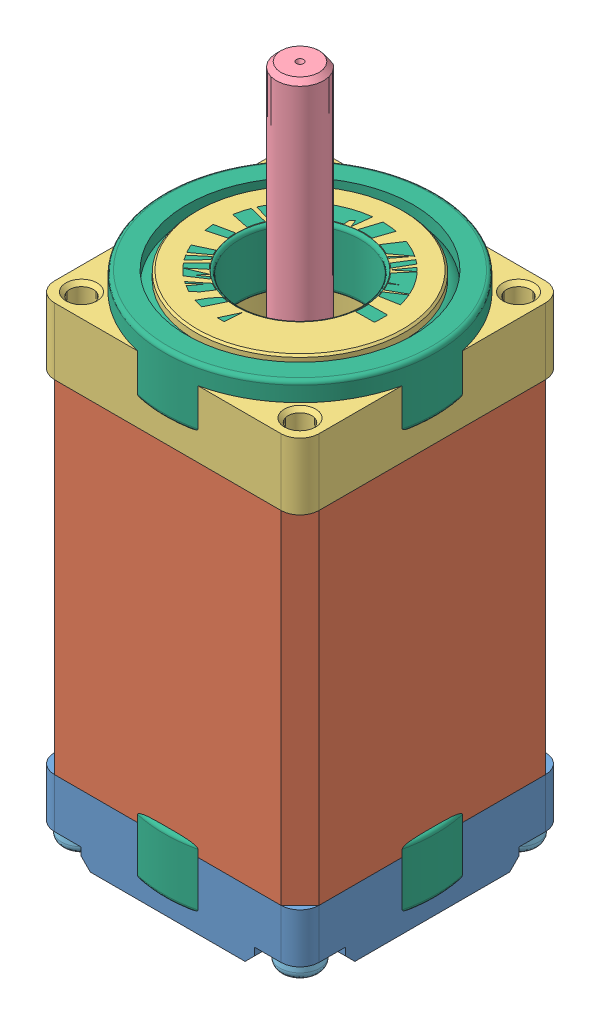
SolidWorks assembly Nema_11_motor_51mm, configuration По умолчанию. Lengths in mm.
Overall size (28.57 71.01 28.57).
10 component instances, 6 part files, 18 mates.
Components (placement in the parent):
- bottom_nema11-1: bottom_nema11 [По умолчанию] at origin size (27.85 7 27.85)
- middle_51_nema11-1: middle_51_nema11 [По умолчанию] at (0 7 0) size (27.85 36 27.85)
- top_nema11-1: top_nema11 [По умолчанию] at (0 43 0) size (27.85 9 27.85)
- shaft_51_nema11-1: shaft_51_nema11 [По умолчанию] at origin size (5 71 5)
- screw_51_nema11-1: screw_51_nema11 [По умолчанию] at (-11.5 1.8 -11.5) size (4.2 45.81 4.2)
- screw_51_nema11-8: screw_51_nema11 [По умолчанию] at (-11.5 1.8 11.5) size (4.2 45.81 4.2)
- screw_51_nema11-9: screw_51_nema11 [По умолчанию] at (11.5 1.8 -11.5) size (4.2 45.81 4.2)
- screw_51_nema11-10: screw_51_nema11 [По умолчанию] at (11.5 1.8 11.5) size (4.2 45.81 4.2)
- instrument ball bearing_68_iso-1: instrument ball bearing_68_iso [ISO 1224 - 190513 - R,Full,SI,NC,Full_68] at (0 48.825 0) x (0 1 0) z (0 0 1) size (6.35 28.57 28.57)
- instrument ball bearing_68_iso-2: instrument ball bearing_68_iso [ISO 1224 - 190513 - R,Full,SI,NC,Full_68] at (0 4.975 0) x (0 -1 0) z (0 0 1) size (6.35 28.57 28.57)
Mates (geometry in assembly coordinates):
- Совпадение1: coincident anti-aligned: plane of bottom_nema11-1 through (0 7 0) normal (0 1 0); plane of middle_51_nema11-1 through (0 7 0) normal (0 -1 0)
- Совпадение2: coincident aligned: plane of bottom_nema11-1 through (13.925 7 0) normal (1 0 0); plane of middle_51_nema11-1 through (13.925 43 13.925) normal (1 0 0)
- Совпадение3: coincident aligned: plane of bottom_nema11-1 through (0 7 13.925) normal (0 0 1); plane of middle_51_nema11-1 through (-13.925 43 13.925) normal (0 0 1)
- Концентричный1: concentric aligned: cylinder of bottom_nema11-1 through (11.5 7 11.5) axis (0 -1 0) radius 1.25; cylinder of top_nema11-1 through (11.5 50 11.5) axis (0 -1 0) radius 1.25
- Концентричный2: concentric aligned: cylinder of bottom_nema11-1 through (-11.5 7 -11.5) axis (0 -1 0) radius 1.25; cylinder of top_nema11-1 through (-11.5 50 -11.5) axis (0 -1 0) radius 1.25
- Совпадение5: coincident aligned: plane of bottom_nema11-1 through (0 0 0) normal (0 -1 0); plane of shaft_51_nema11-1 through (0 0 0) normal (0 -1 0)
- Концентричный4: concentric aligned: cylinder of bottom_nema11-1 through (-11.5 7 -11.5) axis (0 -1 0) radius 1.25; cylinder of screw_51_nema11-1 through (-11.5 45.8 -11.5) axis (0 -1 0) radius 1.25
- Совпадение6: coincident anti-aligned: plane of bottom_nema11-1 through (0 1.8 0) normal (0 -1 0); plane of screw_51_nema11-1 through (-11.5 1.8 -11.5) normal (0 1 0)
- Концентричный6: concentric aligned: cylinder of bottom_nema11-1 through (-11.5 7 11.5) axis (0 -1 0) radius 1.25; cylinder of screw_51_nema11-8 through (-11.5 45.8 11.5) axis (0 -1 0) radius 1.25
- Совпадение7: coincident anti-aligned: plane of bottom_nema11-1 through (0 1.8 0) normal (0 -1 0); plane of screw_51_nema11-8 through (-11.5 1.8 11.5) normal (0 1 0)
- Концентричный7: concentric aligned: cylinder of bottom_nema11-1 through (11.5 7 -11.5) axis (0 -1 0) radius 1.25; cylinder of screw_51_nema11-9 through (11.5 45.8 -11.5) axis (0 -1 0) radius 1.25
- Совпадение8: coincident anti-aligned: plane of bottom_nema11-1 through (0 1.8 0) normal (0 -1 0); plane of screw_51_nema11-9 through (11.5 1.8 -11.5) normal (0 1 0)
- Концентричный8: concentric aligned: cylinder of bottom_nema11-1 through (11.5 7 11.5) axis (0 -1 0) radius 1.25; cylinder of screw_51_nema11-10 through (11.5 45.8 11.5) axis (0 -1 0) radius 1.25
- Совпадение9: coincident anti-aligned: plane of bottom_nema11-1 through (0 1.8 0) normal (0 -1 0); plane of screw_51_nema11-10 through (11.5 1.8 11.5) normal (0 1 0)
- Концентричный9: concentric anti-aligned: cylinder of top_nema11-1 through (0 50 0) axis (0 -1 0) radius 6.5; cylinder of instrument ball bearing_68_iso-1 through (0 28.1875 0) axis (0 1 0) radius 14.2875
- Совпадение10: coincident aligned: plane of top_nema11-1 through (0 52 0) normal (0 1 0); plane of instrument ball bearing_68_iso-1 through (-13.8811 52 0) normal (0 1 0)
- Концентричный10: concentric anti-aligned: cylinder of bottom_nema11-1 through (0 2 0) axis (0 1 0) radius 6.5; cylinder of instrument ball bearing_68_iso-2 through (0 25.6125 0) axis (0 -1 0) radius 14.2875
- Совпадение11: coincident anti-aligned: circle of bottom_nema11-1; plane of instrument ball bearing_68_iso-2 through (13.8811 1.8 0) normal (0 -1 0)
